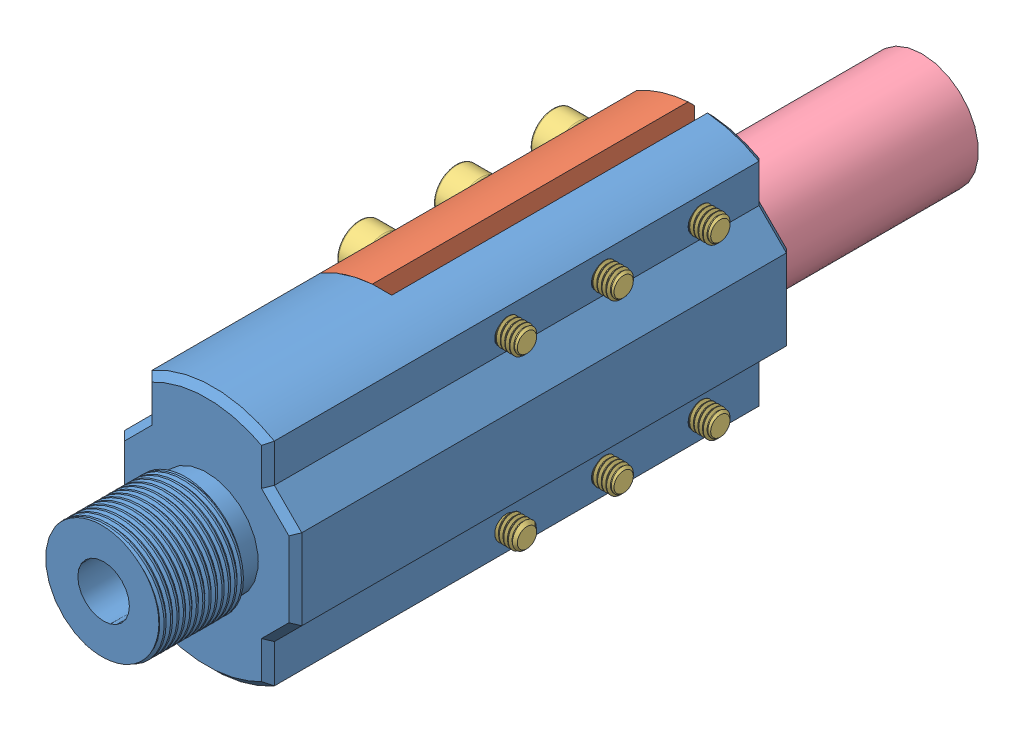
SolidWorks assembly Assemblage1, configuration Défaut. Lengths in mm.
Overall size (29.5 38 127.33).
9 component instances, 4 part files, 19 mates.
Components (placement in the parent):
- piece prinp 3-1: piece prinp 3 [Défaut] at (3.1108 1.6197 53.6005) size (27.5 38 93.53)
- piece second 3-1: piece second 3 [Défaut] at (3.1108 1.6197 53.6005) x (0 1 0) z (0 0 1) size (37.88 12.25 50)
- vis1-1: vis1 [Défaut] at (15.6108 -11.5008 93.6005) x (0 -0.730694 -0.682705) z (-1 0 0) size (7 7 26.11)
- vis1-2: vis1 [Défaut] at (15.6108 -11.5008 78.6005) x (0 0 1) z (-1 0 0) size (7 7 26.11)
- vis1-3: vis1 [Défaut] at (15.6108 -11.5008 63.6005) x (0 0 1) z (-1 0 0) size (7 7 26.11)
- vis1-4: vis1 [Défaut] at (15.6108 14.7401 93.6005) x (0 0 1) z (-1 0 0) size (7 7 26.11)
- vis1-5: vis1 [Défaut] at (15.6108 14.7401 78.6005) x (0 0 1) z (-1 0 0) size (7 7 26.11)
- vis1-6: vis1 [Défaut] at (15.6108 14.7401 63.6005) x (0 0 1) z (-1 0 0) size (7 7 26.11)
- canon-1: canon [Défaut] at (3.1108 1.6197 19.8005) x (0 1 0) z (0 0 1) size (17.5 24.5 100)
Mates (geometry in assembly coordinates):
- Parallèle1: parallel anti-aligned: plane of piece prinp 3-1 through (4.6108 21.6197 103.6005) normal (-1 0 0); plane of piece second 3-1 through (1.6108 22.9421 104.6005) normal (1 0 0)
- Coïncidente2: coincident aligned: plane of piece prinp 3-1 through (-10.6392 24.251 130.8005) normal (-1 0 0); plane of piece second 3-1 through (-10.6392 21.9868 104.6005) normal (-1 0 0)
- Coaxiale1: concentric aligned: circle of piece prinp 3-1; circle of piece second 3-1
- Coaxiale2: concentric aligned: circle of piece prinp 3-1; circle of piece second 3-1
- Coaxiale3: concentric anti-aligned: circle of piece second 3-1; circle of vis1-1
- Coaxiale4: concentric anti-aligned: circle of piece second 3-1; circle of vis1-2
- Coaxiale5: concentric anti-aligned: circle of piece second 3-1; circle of vis1-3
- Coaxiale6: concentric anti-aligned: circle of piece second 3-1; circle of vis1-4
- Coaxiale7: concentric anti-aligned: circle of piece second 3-1; circle of vis1-5
- Coaxiale8: concentric anti-aligned: circle of piece second 3-1; circle of vis1-6
- Coïncidente5: coincident anti-aligned: plane of piece second 3-1 through (-6.3892 12.1197 104.6005) normal (-1 0 0); plane of vis1-6 through (-6.3892 14.7401 63.6005) normal (1 0 0)
- Coïncidente6: coincident anti-aligned: plane of piece second 3-1 through (-6.3892 12.1197 104.6005) normal (-1 0 0); plane of vis1-5 through (-6.3892 14.7401 78.6005) normal (1 0 0)
- Coïncidente7: coincident anti-aligned: plane of piece second 3-1 through (-6.3892 12.1197 104.6005) normal (-1 0 0); plane of vis1-4 through (-6.3892 14.7401 93.6005) normal (1 0 0)
- Coïncidente8: coincident anti-aligned: plane of piece second 3-1 through (-6.3892 -8.8803 104.6005) normal (-1 0 0); plane of vis1-3 through (-6.3892 -11.5008 63.6005) normal (1 0 0)
- Coïncidente9: coincident anti-aligned: plane of piece second 3-1 through (-6.3892 -8.8803 104.6005) normal (-1 0 0); plane of vis1-2 through (-6.3892 -11.5008 78.6005) normal (1 0 0)
- Coïncidente10: coincident anti-aligned: plane of piece second 3-1 through (-6.3892 -8.8803 104.6005) normal (-1 0 0); plane of vis1-1 through (-6.3892 -11.5008 93.6005) normal (1 0 0)
- Coaxiale9: concentric aligned: circle of piece prinp 3-1; circle of canon-1
- Coïncidente11: coincident anti-aligned: plane of piece prinp 3-1 through (3.1108 1.6197 112.6005) normal (0 0 -1); plane of canon-1 through (3.1108 1.6197 112.6005) normal (0 0 1)
- Parallèle2: parallel anti-aligned: plane of piece prinp 3-1 through (-14.8892 -2.9303 112.6005) normal (0 1 0); plane of canon-1 through (-12.6392 -2.9803 112.6005) normal (0 -1 0)
